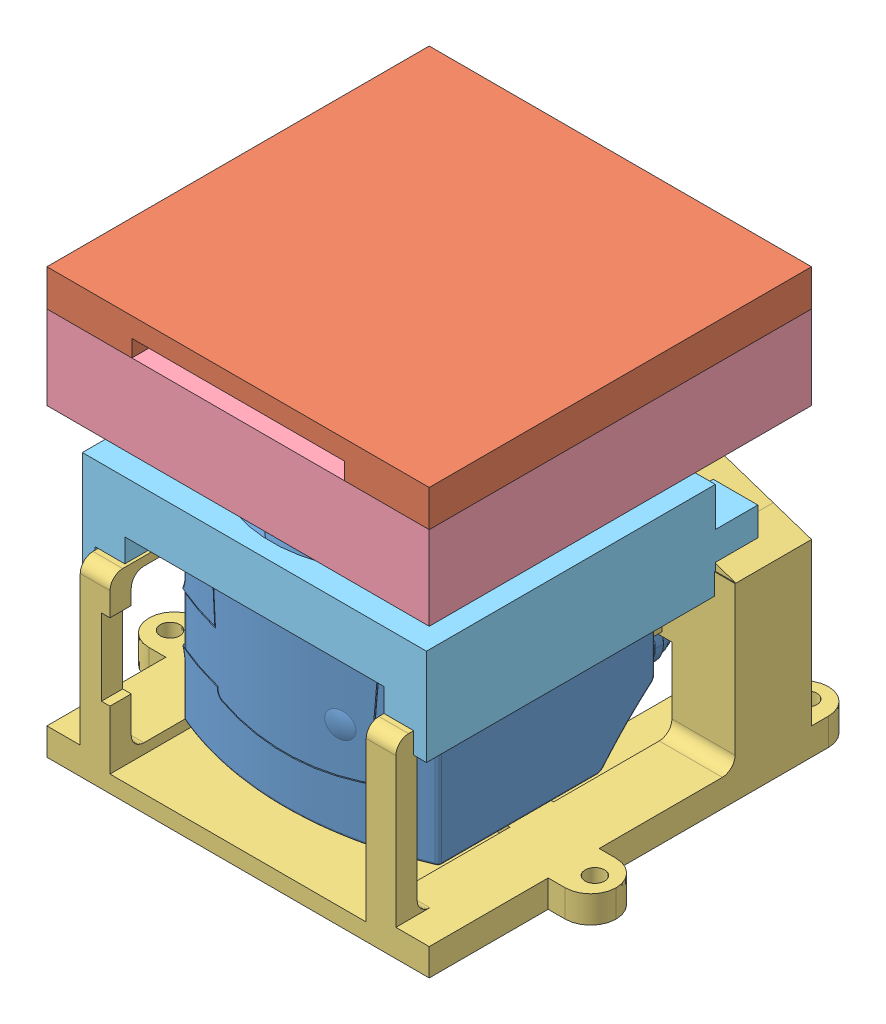
SolidWorks assembly Assemblage Support SICK TIM561 Robot 1, configuration Défaut. Lengths in mm.
Overall size (110 100 100).
6 component instances, 6 part files, 18 mates.
Components (placement in the parent):
- TIM561-Part-1: TIM561-Part [Default] at (151.5091 -60.6837 191.0389) x (0 0 1) z (-1 0 0) size (76.29 86.12 61.14)
- Support Sick TIM562 Haut Robot 1-1: Support Sick TIM562 Haut Robot 1 [Défaut] at (151.5591 -88.2816 186.0889) size (90 36 90)
- Support Sick TIM562 Bas Robot 1-1: Support Sick TIM562 Bas Robot 1 [Défaut] at (151.5591 -88.2816 186.0889) size (110 79 100)
- Cache LiDAR-1: Cache LiDAR [Défaut] at (157.6852 10.4531 155.7173) x (-1 0 0) z (0 0 -1) (suppressed, hidden)
- Cache LiDAR Haut-1: Cache LiDAR Haut [Défaut] at (147.4571 -16.5816 231.0889) x (-1 0 0) z (0 0 -1) size (90 19.7 90)
- Cache LiDAR Bas-1: Cache LiDAR Bas [Défaut] at (156.2052 -38.3816 226.8889) x (-1 0 0) z (0 0 -1) size (81 22.7 78)
Mates (geometry in assembly coordinates):
- Coaxiale1: concentric anti-aligned: cylinder of Support Sick TIM561 MK1 B_M-1 through (19.8407 -7.8632 59.999) axis (0 0 1) radius 1.75; cylinder of TIM561-Part-1 through (177.0091 -59.8416 161.5389) axis (0 0 -1) radius 1.25
- Parallèle1: parallel anti-aligned: cylinder of Support Sick TIM561 MK1 B_M-1 through (-31.1593 -36.3042 121) axis (0 1 0) radius 1.75; cylinder of TIM561-Part-1 through (126.0061 -81.7395 192.0389) axis (0 -1 0) radius 1.25
- Coïncidente1: coincident anti-aligned: plane of Support Sick TIM561 MK1 B_M-1 through (-5.7093 -36.3032 90.45) normal (0 0 1); plane of TIM561-Part-1 through (126.4019 -59.8477 161.5389) normal (0 0 -1)
- Coaxiale2: concentric anti-aligned: cylinder of TIM561-Part-1 through (126.0091 -59.8416 161.5389) axis (0 0 -1) radius 1.25; cylinder of Support Sick TIM562 Bas Robot 1-1 through (126.0091 -59.8416 131.0879) axis (0 0 1) radius 1.75
- Parallèle2: parallel anti-aligned: cylinder of TIM561-Part-1 through (177.0091 -59.8416 161.5389) axis (0 0 -1) radius 1.25; cylinder of Support Sick TIM562 Bas Robot 1-1 through (177.1091 -59.8416 131.0879) axis (0 0 1) radius 1.75
- Coïncidente2: coincident anti-aligned: plane of TIM561-Part-1 through (126.4019 -59.8477 161.5389) normal (0 0 -1); plane of Support Sick TIM562 Bas Robot 1-1 through (151.5591 -88.2816 161.5389) normal (0 0 1)
- Coïncidente9: coincident anti-aligned: plane of Support Sick TIM562 Haut Robot 1-1 through (151.5591 -9.2816 186.0889) normal (0 -1 0); plane of Support Sick TIM562 Bas Robot 1-1 through (151.5591 -9.2816 186.0889) normal (0 1 0)
- Coïncidente10: coincident aligned: plane of Support Sick TIM562 Haut Robot 1-1 through (106.5591 -84.2816 141.0889) normal (0 0 -1); plane of Support Sick TIM562 Bas Robot 1-1 through (106.5591 -84.2816 141.0889) normal (0 0 -1)
- Coïncidente11: coincident aligned: plane of Support Sick TIM562 Haut Robot 1-1 through (144.0591 3.1184 141.0889) normal (-1 0 0); plane of Support Sick TIM562 Bas Robot 1-1 through (144.0591 3.1184 141.0889) normal (-1 0 0)
- Coïncidente12: coincident anti-aligned: plane of Support Sick TIM562 Bas Robot 1-1 through (151.5591 -43.8816 186.0889) normal (0 1 0); plane of Cache LiDAR-1 through (122.189 4.9531 87.7173) normal (0 -1 0)
- Coïncidente13: coincident anti-aligned: line of Support Sick TIM562 Bas Robot 1-1 through (106.5591 -43.8816 158.8889) axis (1 0 0); line of Cache LiDAR-1 through (122.189 4.9531 87.7173) axis (-1 0 0)
- Coïncidente14: coincident aligned: line of Support Sick TIM562 Bas Robot 1-1 through (121.4091 -43.8816 158.8889) axis (0 0 1); line of Cache LiDAR-1 through (122.189 4.9531 87.7173) axis (0 0 1)
- Coïncidente15: coincident anti-aligned: plane of Support Sick TIM562 Haut Robot 1-1 through (151.5591 3.1184 186.0889) normal (0 -1 0); plane of Cache LiDAR Haut-1 through (196.5591 3.1184 141.0889) normal (0 1 0)
- Coïncidente16: coincident aligned: line of Support Sick TIM562 Haut Robot 1-1 through (106.5591 3.1184 141.0889) axis (0 0 1); line of Cache LiDAR Haut-1 through (106.5591 3.1184 141.0889) axis (0 0 1)
- Coïncidente17: coincident aligned: line of Support Sick TIM562 Haut Robot 1-1 through (106.5591 3.1184 231.0889) axis (1 0 0); line of Cache LiDAR Haut-1 through (106.5591 3.1184 231.0889) axis (1 0 0)
- Coïncidente20: coincident anti-aligned: plane of Support Sick TIM562 Bas Robot 1-1 through (151.5591 -43.8816 186.0889) normal (0 1 0); plane of Cache LiDAR Bas-1 through (188.7091 -43.8816 158.8889) normal (0 -1 0)
- Coïncidente21: coincident anti-aligned: line of Support Sick TIM562 Bas Robot 1-1 through (181.7091 -43.8816 158.8889) axis (1 0 0); line of Cache LiDAR Bas-1 through (188.7091 -43.8816 158.8889) axis (-1 0 0)
- Coïncidente22: coincident anti-aligned: line of Support Sick TIM562 Bas Robot 1-1 through (188.7091 -43.8816 228.0889) axis (0 0 -1); line of Cache LiDAR Bas-1 through (188.7091 -43.8816 158.8889) axis (0 0 1)
